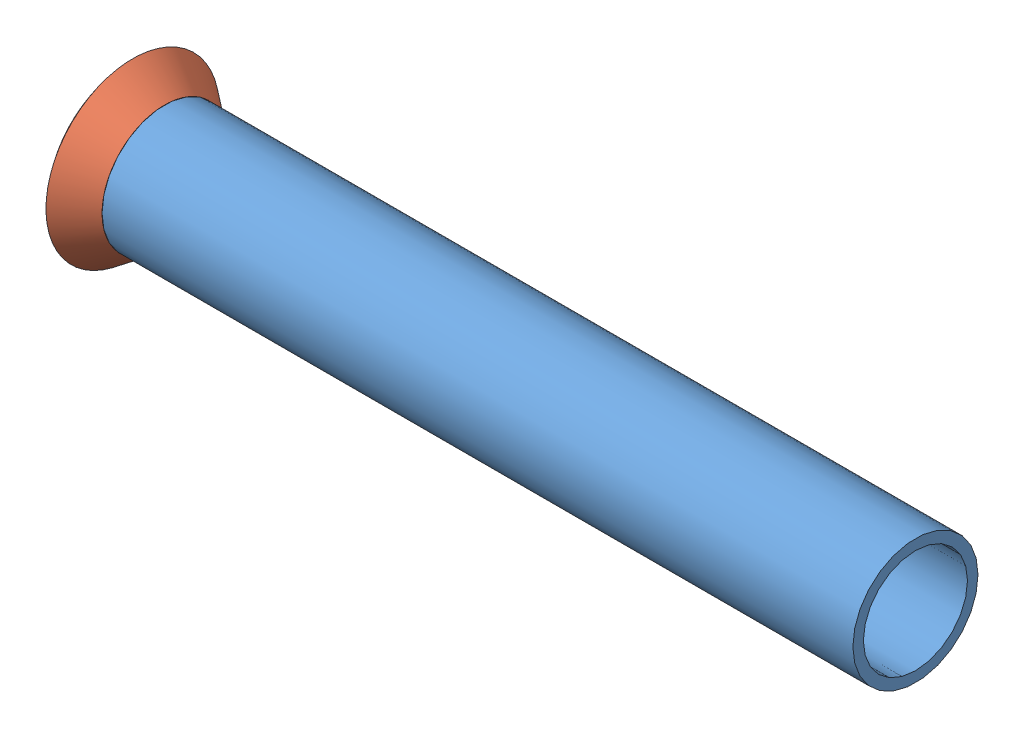
SolidWorks assembly Pipe 45, configuration Default. Lengths in mm.
Overall size (80.09 17.59 17.59).
2 component instances, 2 part files, 2 mates.
Components (placement in the parent):
- Copy of Part1^Pipe 45-1: Copy of Part1^Pipe 45 [Default<As Machined>] at (-618.6065 -1173.3948 485.9354) x (-1 0 0) z (0 0 -1) size (76.2 12.7 12.7) (virtual)
- Flared pipe end - .5 inch-1: Flared pipe end - .5 inch [Default<As Machined>] at (-846.8165 452.6099 485.9354) x (0 0 1) z (-1 0 0) size (17.59 17.59 3.89)
Mates (geometry in assembly coordinates):
- Coincident1415: coincident: plane of Copy of Part1^Pipe 45-1 through (-846.8165 452.6099 485.9354) normal (-1 0 0); plane of Flared pipe end - .5 inch-1 through (-846.8165 457.8931 485.9354) normal (1 0 0)
- Coincident1416: coincident: cylinder of Copy of Part1^Pipe 45-1 through (-846.8165 452.6099 485.9354) axis (1 0 0) radius 5.2832; circle of Flared pipe end - .5 inch-1
